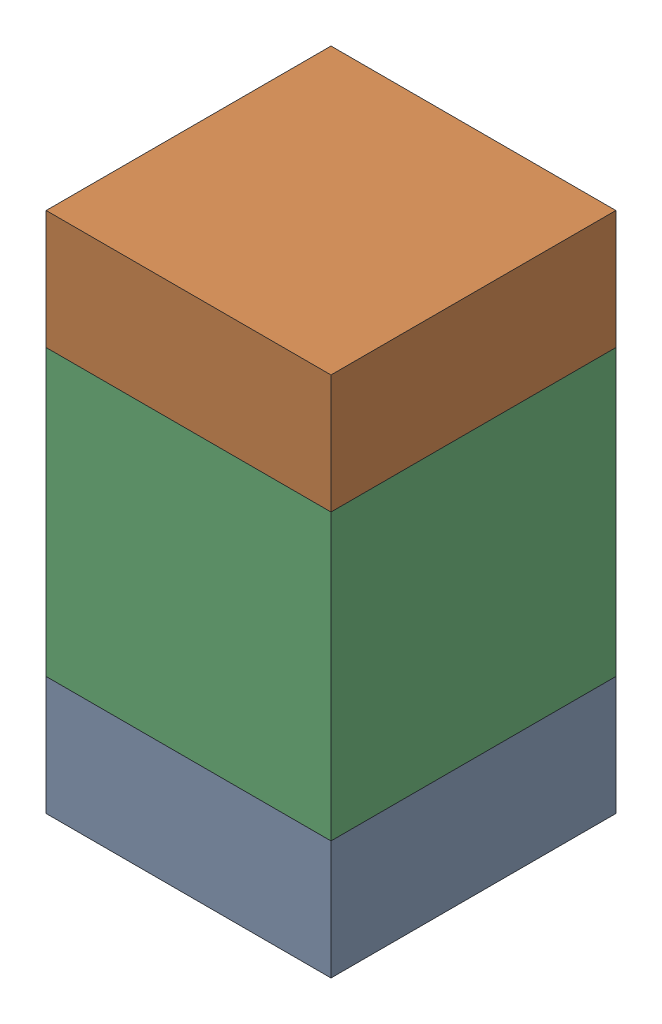
SolidWorks assembly C101_1PCB, configuration Default. Lengths in mm.
Overall size (0.6 1.1 0.6).
6 component instances, 2 part files, 0 mates.
Components (placement in the parent):
- 854785296-1: 854785296 [Default] at (108.9 120.875 0) size (0.6 0.25 0.6)
  - Extruded_10-1: Extruded_10 [Default] at origin size (0.6 0.25 0.6)
- 854785296-2: 854785296 [Default] at (108.9 121.725 0) size (0.6 0.25 0.6)
  - Extruded_10-1: Extruded_10 [Default] at origin size (0.6 0.25 0.6)
- 761606048-1: 761606048 [Default] at (108.9 121.3 0) size (0.6 0.6 0.6)
  - Extruded_9-1: Extruded_9 [Default] at origin size (0.6 0.6 0.6)
